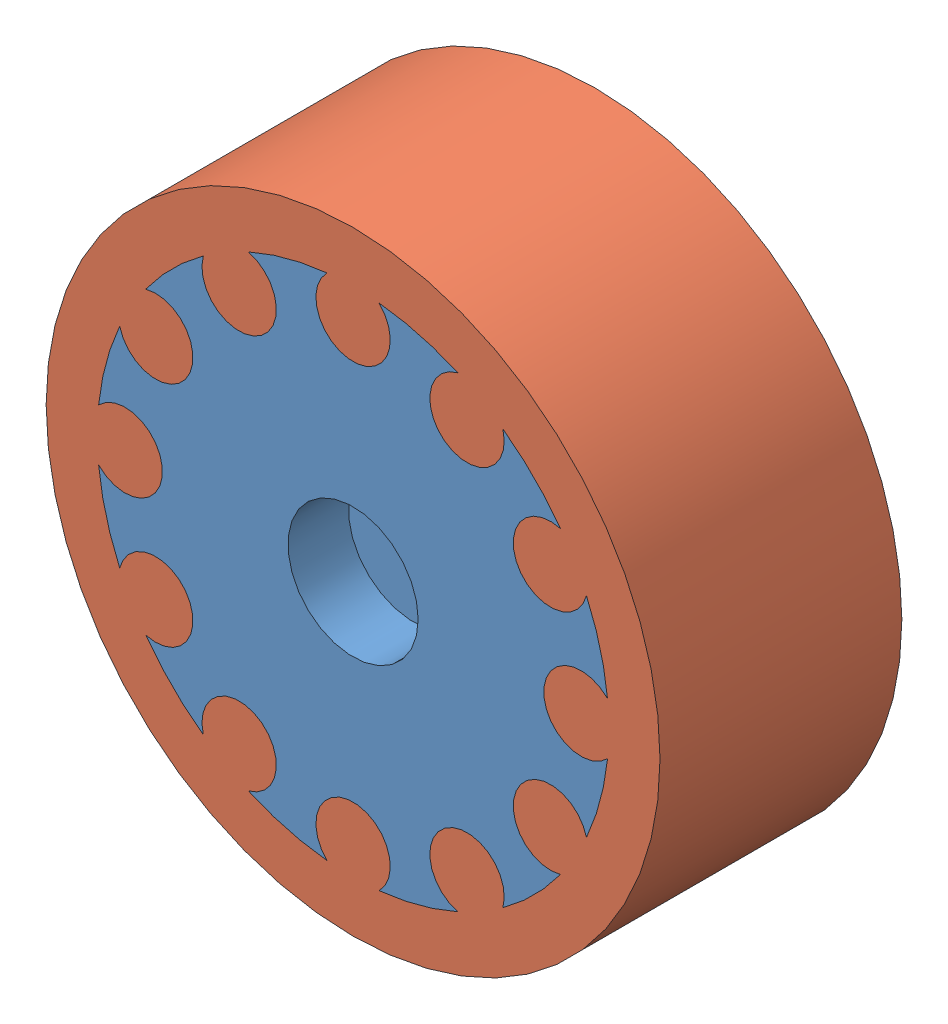
SolidWorks assembly Ens, configuration Predeterminado. Lengths in mm.
Overall size (66 66 26).
2 component instances, 2 part files, 3 mates.
Components (placement in the parent):
- llanta-1: llanta [Predeterminado] at (0.1185 -1.4811 54.7143) size (54.71 54.71 26)
- Rueda-1: Rueda [Predeterminado] at (0.1185 -1.4811 54.7143) size (66 66 26)
Mates (geometry in assembly coordinates):
- Concéntrica1: concentric aligned: circle of llanta-1; circle of Rueda-1
- Coincidente1: coincident aligned: plane of llanta-1 through (7.1185 -1.4811 67.7143) normal (0 0 1); plane of Rueda-1 through (0.1185 -1.4811 67.7143) normal (0 0 1)
- Coincidente2: coincident aligned: circle of llanta-1; circle of Rueda-1
